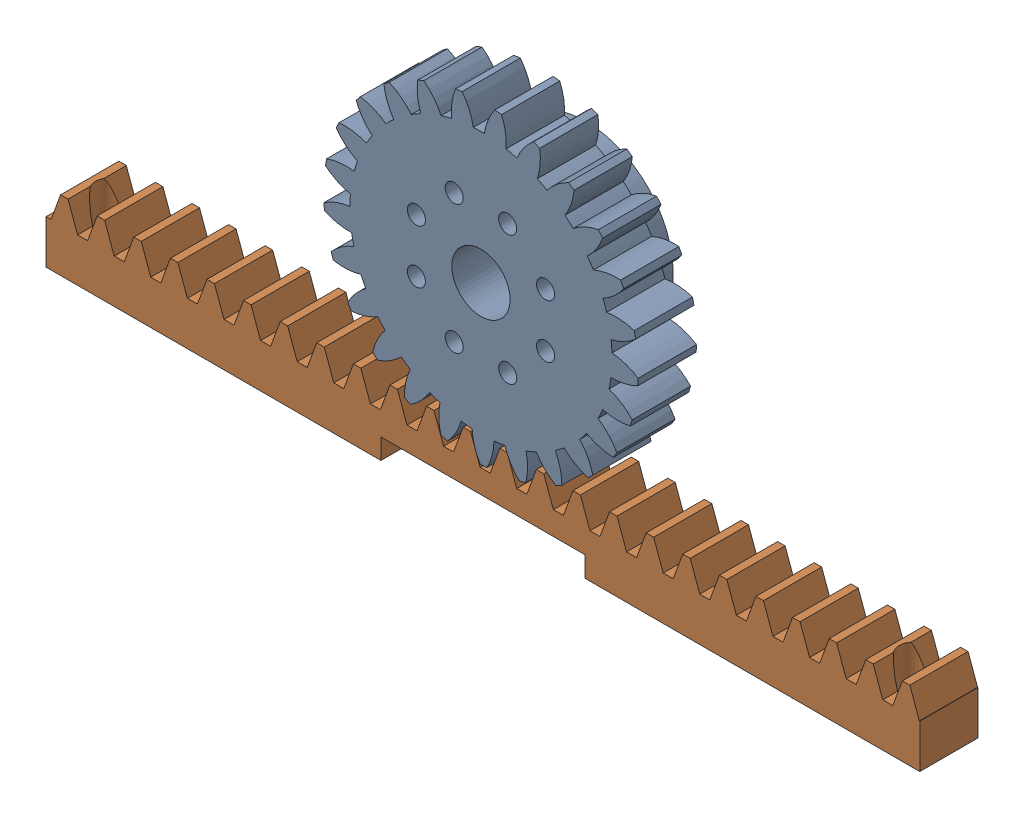
SolidWorks assembly Rack and Pinion, configuration Default. Lengths in mm.
Overall size (150.33 70.41 18).
2 component instances, 2 part files, 5 mates.
Components (placement in the parent):
- Pinion-3: Pinion [Metric - Spur gear 2M 25T 20PA 10FW ---S25N75H50L10N] at (0 0 -10) x (0 0 1) z (0.923728 0.383049 0) size (18 53.85 53.95)
- Rack-2: Rack [Metric - Rack-spur - rectangular 2M 20PA 10FW 10PH 150L---SAll] at (-74.6735 -35 0) size (150 12 10)
Mates (geometry in assembly coordinates):
- Concentric2: concentric: cylinder of Pinion-3 through (0 0 40.0001) axis (0 0 -1) radius 5
- Coincident3: coincident aligned: plane of Pinion-3 through (0 0 0) normal (0 0 1)
- Coincident4: coincident aligned: moEndPointRef_w of Rack-2
- Coincident6: coincident aligned: plane of Pinion-3 through (0 0 0) normal (0 0 1); plane of Rack-2 through (-74.6735 -23 0) normal (0 0 1)
- Coincident7: coincident aligned: line of Rack-2 through (17.8265 -35 0) axis (1 0 0)
